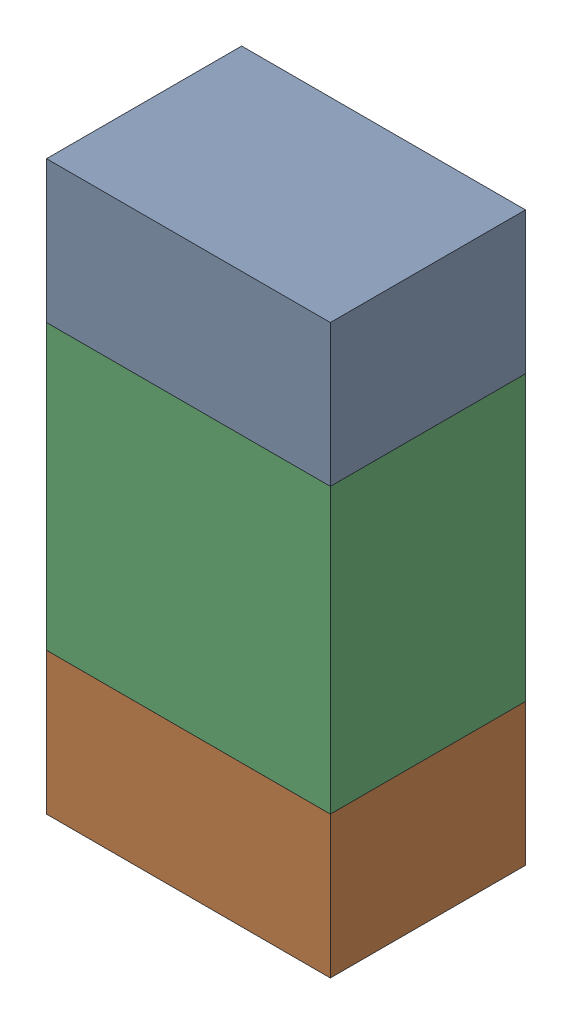
SolidWorks assembly R58, configuration ﾃﾞﾌｫﾙﾄ. Lengths in mm.
Overall size (0.8 1.6 0.55).
6 component instances, 2 part files, 0 mates.
Components (placement in the parent):
- 689261784-1: 689261784 [ﾃﾞﾌｫﾙﾄ] at (42.5999 33.5999 -1.7503) size (0.8 0.4 0.55)
  - Extruded_34-1: Extruded_34 [ﾃﾞﾌｫﾙﾄ] at origin size (0.8 0.4 0.55)
- 689261784-2: 689261784 [ﾃﾞﾌｫﾙﾄ] at (42.5999 32.3999 -1.7503) size (0.8 0.4 0.55)
  - Extruded_34-1: Extruded_34 [ﾃﾞﾌｫﾙﾄ] at origin size (0.8 0.4 0.55)
- 689261648-1: 689261648 [ﾃﾞﾌｫﾙﾄ] at (42.5999 33 -1.7503) size (0.8 0.8 0.55)
  - Extruded_33-1: Extruded_33 [ﾃﾞﾌｫﾙﾄ] at origin size (0.8 0.8 0.55)
